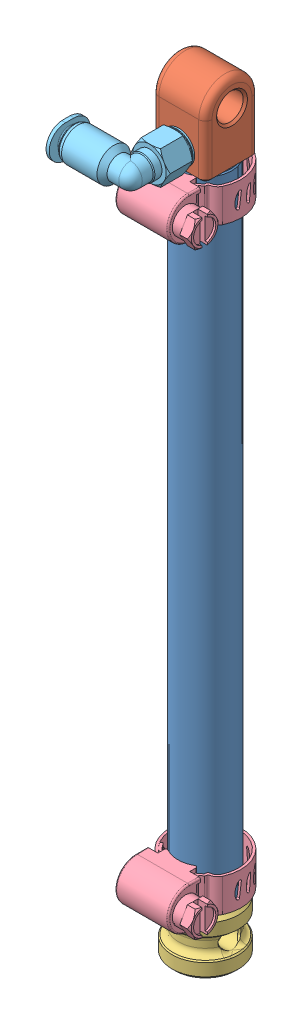
SolidWorks assembly AARL_QR_PN_PA_BL_AN_FL-Flexor, configuration Default. Lengths in mm.
Overall size (26.6 184.15 31.28).
6 component instances, 5 part files, 15 mates.
Components (placement in the parent):
- AARL_QR_PN_PA_BL_AN_FL_001-1: AARL_QR_PN_PA_BL_AN_FL_001 [Resting] at origin size (12.7 152.4 12.7)
- AARL_QR_PN_EP_001-1: AARL_QR_PN_EP_001 [Default] at (0 88.9 0) x (0 0 1) z (-1 0 0) size (12.7 31.75 12.7)
- AARL_QR_PN_EP_002-1: AARL_QR_PN_EP_002 [Default] at (0 -76.2 0) x (1 0 0) z (0 0 -1) size (15.88 25.4 15.88)
- AARL_Puppy_18_02_57_011-5388K140_Hose-Clamp-1: AARL_Puppy_18_02_57_011-5388K140_Hose-Clamp [5388K14] at (0 -71.247 0) x (1 0 0) z (0 -1 0) size (19.43 23.71 9.91)
- AARL_Puppy_18_02_57_011-5388K140_Hose-Clamp-2: AARL_Puppy_18_02_57_011-5388K140_Hose-Clamp [5388K14] at (0 71.247 0) x (1 0 0) z (0 -1 0) size (19.43 23.71 9.91)
- AARL_Puppy_18_02_57_010-QSML-M3-4-1: AARL_Puppy_18_02_57_010-QSML-M3-4 [Default] at (0 80.9625 17.85) x (-1 0 0) z (0 0 -1) size (20.32 8 18.9)
Mates (geometry in assembly coordinates):
- Concentric1: concentric aligned: cylinder of AARL_QR_PN_PA_BL_AN_FL_001-1 through (0 11.6086 0) axis (0 1 0) radius 4.7625; cylinder of AARL_QR_PN_EP_001-1 through (0 98.444 0) axis (0 1 0) radius 4.3656
- Parallel1: parallel aligned: plane of AARL_QR_PN_EP_001-1 through (-6.35 76.2 6.35) normal (0 0 1)
- Coincident2: coincident anti-aligned: plane of AARL_QR_PN_PA_BL_AN_FL_001-1 through (4.7625 76.2 0) normal (0 1 0); plane of AARL_QR_PN_EP_001-1 through (-6.35 76.2 -6.35) normal (0 -1 0)
- Concentric2: concentric anti-aligned: cylinder of AARL_QR_PN_PA_BL_AN_FL_001-1 through (0 11.6086 0) axis (0 1 0) radius 4.7625; cylinder of AARL_QR_PN_EP_002-1 through (0 -83.9377 0) axis (0 -1 0) radius 4.3656
- Parallel2: parallel aligned: cylinder of AARL_QR_PN_EP_001-1 through (-6.35 88.9 0) axis (1 0 0) radius 3.175; cylinder of AARL_QR_PN_EP_002-1 through (-7.9375 -82.55 0) axis (1 0 0) radius 2.3813
- Coincident3: coincident anti-aligned: plane of AARL_QR_PN_PA_BL_AN_FL_001-1 through (6.35 -76.2 0) normal (0 -1 0); plane of AARL_QR_PN_EP_002-1 through (4.3656 -76.2 0) normal (0 1 0)
- Concentric4: concentric aligned: cylinder of AARL_QR_PN_EP_001-1 through (0 80.9625 6.35) axis (0 0 1) radius 2.0193; cylinder of AARL_Puppy_18_02_57_010-QSML-M3-4-1 through (0 80.9625 6.35) axis (0 0 1) radius 1.5
- Coincident4: coincident anti-aligned: plane of AARL_QR_PN_EP_001-1 through (-6.35 76.2 6.35) normal (0 0 1); plane of AARL_Puppy_18_02_57_010-QSML-M3-4-1 through (0 80.9625 6.35) normal (0 0 -1)
- Parallel3: parallel aligned: plane of AARL_QR_PN_EP_001-1 through (-6.35 76.2 -6.35) normal (0 -1 0); plane of AARL_Puppy_18_02_57_010-QSML-M3-4-1 through (2.3094 76.9625 13.4056) normal (0 -1 0)
- Concentric5: concentric aligned: cylinder of AARL_QR_PN_PA_BL_AN_FL_001-1 through (0 11.6086 0) axis (0 1 0) radius 6.35; cylinder of AARL_Puppy_18_02_57_011-5388K140_Hose-Clamp-2 through (0 67.2782 0) axis (0 1 0) radius 7.9375
- Coincident6: coincident aligned: plane of AARL_QR_PN_EP_001-1 through (6.35 88.9 0) normal (1 0 0); plane of AARL_Puppy_18_02_57_011-5388K140_Hose-Clamp-2 through (6.35 71.247 10.2337) normal (1 0 0)
- Coincident7: coincident anti-aligned: plane of AARL_QR_PN_EP_001-1 through (-6.35 76.2 -6.35) normal (0 -1 0); plane of AARL_Puppy_18_02_57_011-5388K140_Hose-Clamp-2 through (0 76.2 0) normal (0 1 0)
- Concentric6: concentric aligned: cylinder of AARL_QR_PN_PA_BL_AN_FL_001-1 through (0 11.6086 0) axis (0 1 0) radius 6.35; cylinder of AARL_Puppy_18_02_57_011-5388K140_Hose-Clamp-1 through (0 -75.2157 0) axis (0 1 0) radius 7.9375
- Coincident8: coincident aligned: plane of AARL_Puppy_18_02_57_011-5388K140_Hose-Clamp-1 through (6.35 -71.247 10.2337) normal (1 0 0); plane of AARL_Puppy_18_02_57_011-5388K140_Hose-Clamp-2 through (6.35 71.247 10.2337) normal (1 0 0)
- Coincident9: coincident anti-aligned: plane of AARL_QR_PN_EP_002-1 through (4.3656 -76.2 0) normal (0 1 0); plane of AARL_Puppy_18_02_57_011-5388K140_Hose-Clamp-1 through (0 -76.2 0) normal (0 -1 0)
